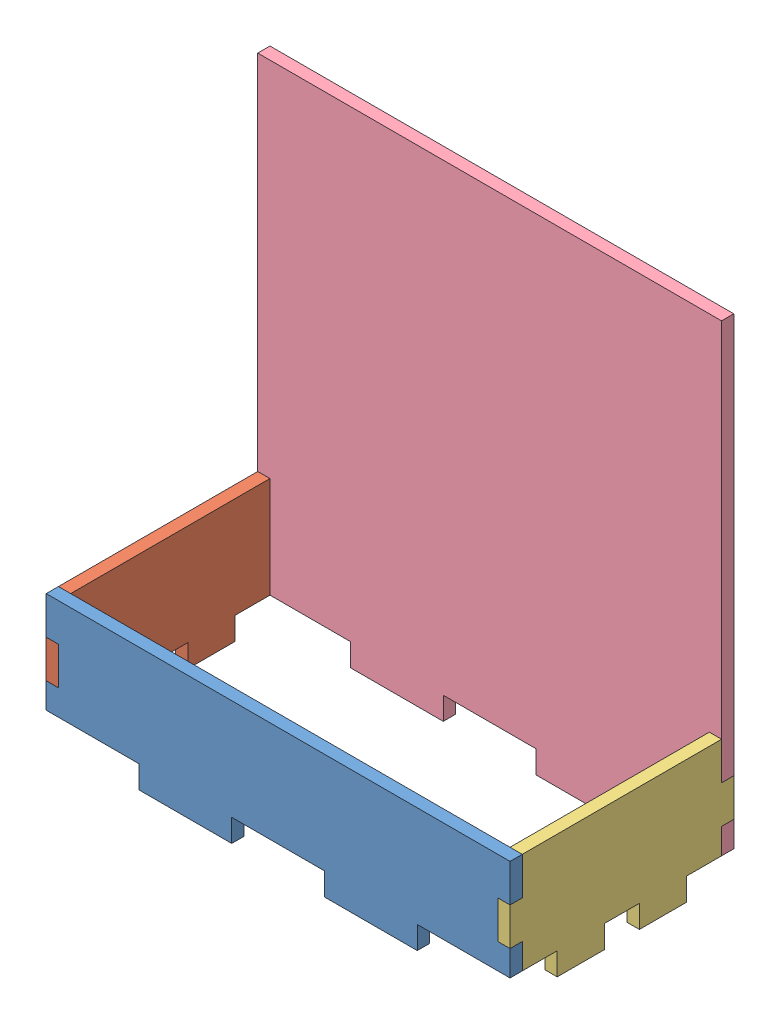
SolidWorks assembly Assem_bat_holder, configuration Varsayılan. Lengths in mm.
Overall size (102.4 107.3 49.4).
4 component instances, 4 part files, 11 mates.
Components (placement in the parent):
- bat_long_wall_1-1: bat_long_wall_1 [Varsayılan] at (-17.3147 -26.3961 101.05) size (102.4 27.3 2.7)
- bat_short_wall_1-1: bat_short_wall_1 [Varsayılan] at (-68.5147 -26.3961 79.05) size (2.7 27.3 49.4)
- bat_short_wall_2-1: bat_short_wall_2 [Varsayılan] at (31.1853 -26.3961 79.05) size (2.7 27.3 49.4)
- bat_long_wall_with_circuit_holder-2: bat_long_wall_with_circuit_holder [Varsayılan] at (-17.3147 -26.3961 54.35) size (102.4 107.3 2.7)
Mates (geometry in assembly coordinates):
- Coincident1: coincident aligned: plane of bat_long_wall_1-1 through (-17.3147 -26.3961 103.75) normal (0 0 1); plane of bat_short_wall_2-1 through (33.8853 -30.5628 103.75) normal (0 0 1)
- Coincident2: coincident aligned: plane of bat_long_wall_1-1 through (33.8853 -22.2295 103.75) normal (1 0 0); plane of bat_short_wall_2-1 through (33.8853 -26.3961 79.05) normal (1 0 0)
- Coincident3: coincident anti-aligned: plane of bat_long_wall_1-1 through (33.8853 -22.2295 103.75) normal (0 -1 0); plane of bat_short_wall_2-1 through (33.8853 -22.2295 103.75) normal (0 1 0)
- Coincident4: coincident aligned: plane of bat_long_wall_1-1 through (-17.3147 -26.3961 103.75) normal (0 0 1); plane of bat_short_wall_1-1 through (-65.8147 -30.5628 103.75) normal (0 0 1)
- Coincident5: coincident aligned: plane of bat_long_wall_1-1 through (-68.5147 -22.2295 103.75) normal (-1 0 0); plane of bat_short_wall_1-1 through (-68.5147 -26.3961 79.05) normal (-1 0 0)
- Coincident6: coincident anti-aligned: plane of bat_long_wall_1-1 through (-68.5147 -30.5628 103.75) normal (0 1 0); plane of bat_short_wall_1-1 through (-65.8147 -30.5628 103.75) normal (0 -1 0)
- Coincident7: coincident anti-aligned: plane of ? through (-65.8147 -102.2295 69.1085) normal (-1 0 0); plane of bat_short_wall_1-1 through (-65.8147 -26.3961 79.05) normal (1 0 0)
- Coincident8: coincident aligned: plane of ? through (-68.5147 -13.8961 69.1085) normal (0 1 0); plane of bat_short_wall_1-1 through (-65.8147 -13.8961 57.05) normal (0 1 0)
- Coincident10: coincident: plane of bat_short_wall_2-1 through (31.1853 -26.3961 79.05) normal (-1 0 0); plane of bat_long_wall_with_circuit_holder-2 through (31.1853 -22.2295 57.05) normal (1 0 0)
- Coincident11: coincident: plane of bat_short_wall_2-1 through (33.8853 -30.5628 54.35) normal (0 0 -1); plane of bat_long_wall_with_circuit_holder-2 through (-17.3147 -26.3961 54.35) normal (0 0 -1)
- Coincident13: coincident anti-aligned: plane of bat_short_wall_2-1 through (33.8853 -22.2295 54.35) normal (0 1 0); plane of bat_long_wall_with_circuit_holder-2 through (33.8853 -22.2295 57.05) normal (0 -1 0)
